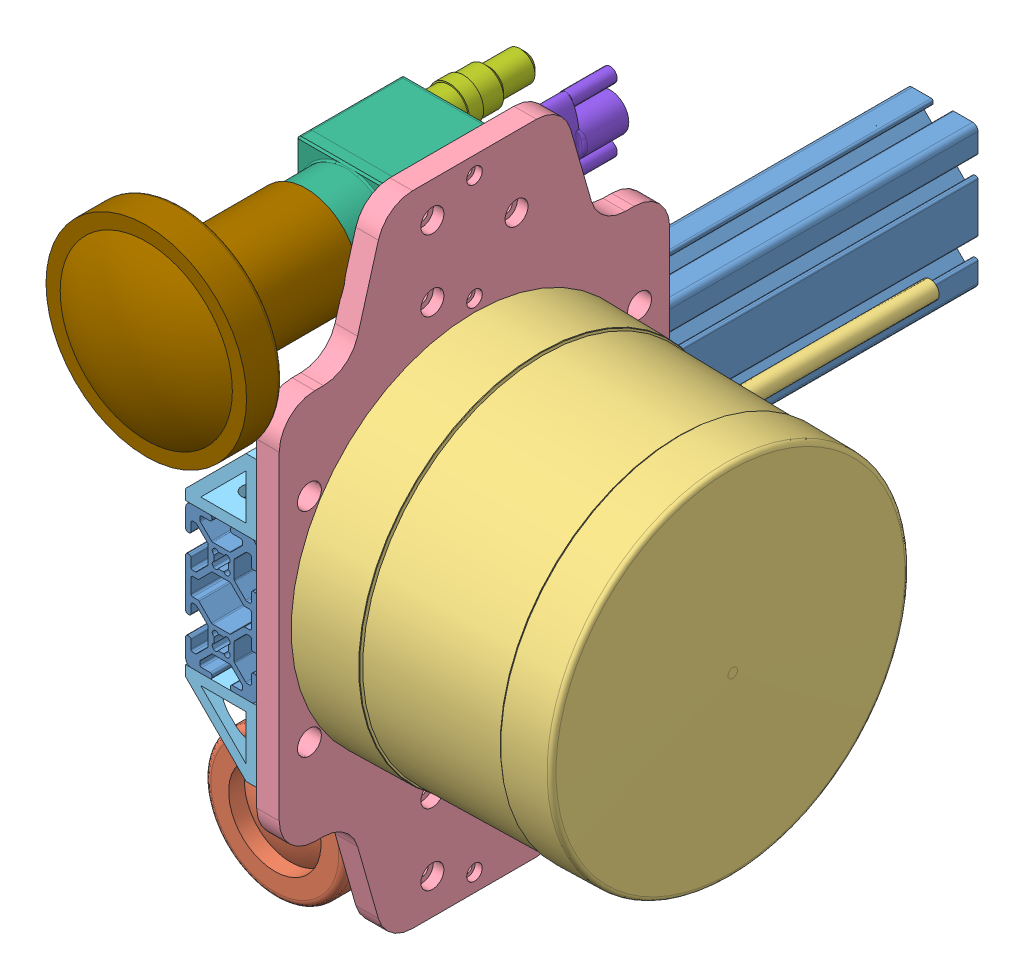
SolidWorks assembly vertical_sensing, configuration Default. Lengths in mm.
Overall size (130.51 199.14 259.7).
13 component instances, 9 part files, 13 mates.
Components (placement in the parent):
- 20-2040-Black-203_2-CL-1: 20-2040-Black-203_2-CL [Default] at origin size (20 40 203.2)
- vue-1: vue [Default] at (-12.5 -60 -82.5) x (0 1 0) z (0 0 1) size (44.45 44.45 57.4)
- VLP-16-1: VLP-16 [Default] at (16.35 10 -55) x (0 0 -1) z (0 -1 0) size (232.88 72.75 103.27)
- everything_plate-1: everything_plate [Default] at (10 10 -55) x (0 0 -1) z (0 -1 0) size (110 9.53 180)
- 5537T663_T-Slotted Framing_Gusset_Bracket-1: 5537T663_T-Slotted Framing_Gusset_Bracket [5537T663] at (0 40 -18.5) x (-1 0 0) z (0 0 -1) size (20 20 37)
- 5537T663_T-Slotted Framing_Gusset_Bracket-2: 5537T663_T-Slotted Framing_Gusset_Bracket [5537T663] at (0 -20 -18.5) x (-1 0 0) z (0 0 1) size (20 20 37)
- 5537T663_T-Slotted Framing_Gusset_Bracket-3: 5537T663_T-Slotted Framing_Gusset_Bracket [5537T663] at (0 40 -91.5) x (-1 0 0) z (0 0 -1) size (20 20 37)
- 5537T663_T-Slotted Framing_Gusset_Bracket-4: 5537T663_T-Slotted Framing_Gusset_Bracket [5537T663] at (0 -20 -91.5) x (-1 0 0) z (0 0 1) size (20 20 37)
- BFS_U3_fisheye-1: BFS_U3_fisheye [Default] at (-4.5 80 -53.0318) x (0 1 0) z (0 0 1) size (73.83 73.83 128.56)
  - FL2-020-R0-1: FL2-020-R0 [Default] at origin size (29 29 47.76)
  - round_connector-1: round_connector [Default] at (7.25 7.25 -17.9182) x (0 0 -1) z (-0.517634 -0.855602 0) size (26.5 11.5 11.5)
  - wide_connector-1: wide_connector [Default] at (0 -9.325 -18.2182) x (1 0 0) z (0 0 -1) size (22 10.5 33.5)
  - FE185C086HA_1-2: FE185C086HA_1 [Default] at (0 0 16.3398) x (-0.923728 -0.383049 0) z (0 0 -1) size (56.5 56.5 60.5)
Mates (geometry in assembly coordinates):
- ProfileCenter1: profile center: circle of VLP-16-1; circle of everything_plate-1
- Width1: width aligned: plane of everything_plate-1 through (16.35 -45 0) normal (0 -1 0); plane of 20-2040-Black-203_2-CL-1 through (16.35 65 0) normal (0 1 0); plane of everything_plate-1 through (8.5 -10 0) normal (0 -1 0); plane of 20-2040-Black-203_2-CL-1 through (3.138 30 0) normal (0 1 0)
- Coincident1: coincident anti-aligned: plane of 20-2040-Black-203_2-CL-1 through (10 16.862 0) normal (1 0 0); plane of everything_plate-1 through (10 10 -55) normal (-1 0 0)
- Coincident2: coincident aligned: plane of 20-2040-Black-203_2-CL-1 through (0 10 0) normal (0 0 1); plane of everything_plate-1 through (16.35 -45 0) normal (0 0 1)
- Coincident3: coincident anti-aligned: plane of 20-2040-Black-203_2-CL-1 through (3.138 30 0) normal (0 1 0); plane of 5537T663_T-Slotted Framing_Gusset_Bracket-1 through (10 30 0) normal (0 -1 0)
- Coincident4: coincident anti-aligned: plane of everything_plate-1 through (10 10 -55) normal (-1 0 0); plane of 5537T663_T-Slotted Framing_Gusset_Bracket-1 through (10 50 0) normal (1 0 0)
- Coincident5: coincident aligned: plane of everything_plate-1 through (16.35 -45 0) normal (0 0 1); plane of 5537T663_T-Slotted Framing_Gusset_Bracket-1 through (0 40 0) normal (0 0 1)
- ProfileCenter2: profile center aligned: circle of vue-1; circle of everything_plate-1
- Parallel1: parallel aligned: plane of vue-1 through (-12.5 -82.225 -57.5) normal (0 -1 0); plane of everything_plate-1 through (16.35 -80 -80) normal (0 -1 0)
- Concentric2: concentric aligned: cylinder of everything_plate-1 through (16.35 80 -66.85) axis (1 0 0) radius 1.8; cylinder of BFS_U3_fisheye-1/FL2-020-R0-1 through (10 80 -66.85) axis (1 0 0) radius 1.5
- Concentric3: concentric aligned: cylinder of everything_plate-1 through (16.35 90 -43.15) axis (1 0 0) radius 3.25; cylinder of BFS_U3_fisheye-1/FL2-020-R0-1 through (10 90 -43.15) axis (1 0 0) radius 1.5
- Coincident6: coincident anti-aligned: plane of everything_plate-1 through (10 10 -55) normal (-1 0 0); plane of BFS_U3_fisheye-1/FL2-020-R0-1 through (10 66.5 -43.65) normal (1 0 0)
- Parallel2: parallel aligned: plane of 20-2040-Black-203_2-CL-1 through (0 10 -203.2) normal (0 0 -1); plane of VLP-16-1
